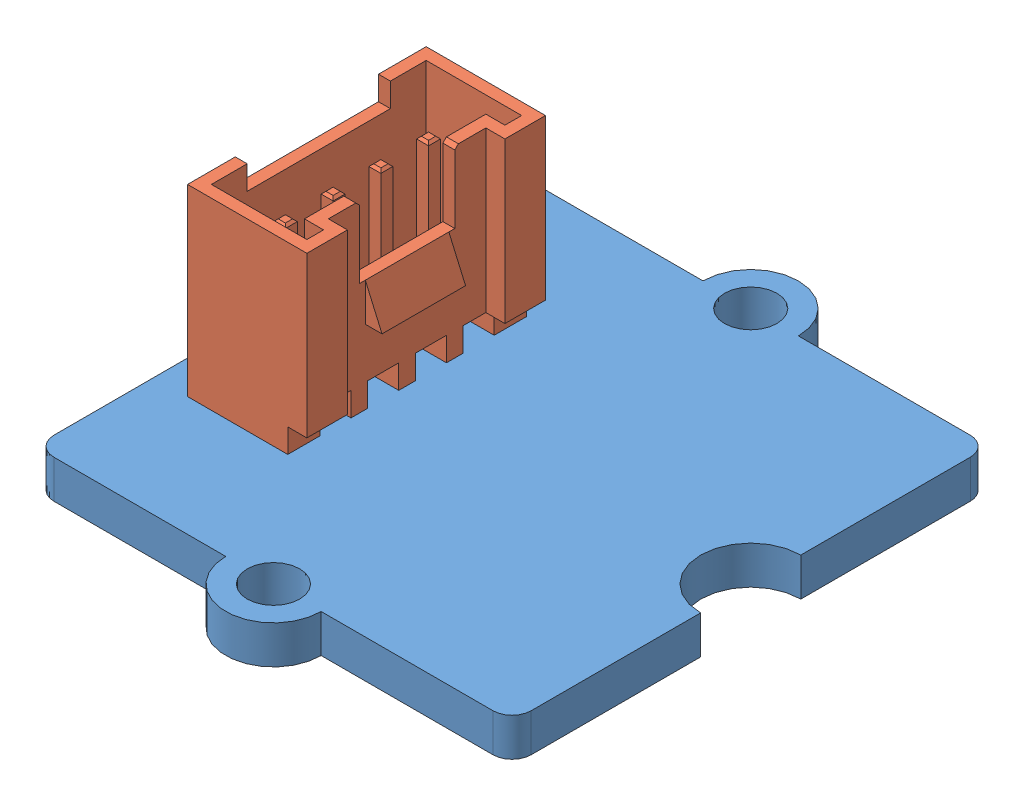
SolidWorks assembly PCB Grove 20x20 DIP - Buzzer, configuration Défaut. Lengths in mm.
Overall size (20 10 24).
2 component instances, 2 part files, 3 mates.
Components (placement in the parent):
- PCB Grove 20x20 - Buzzer v1.2-1: PCB Grove 20x20 - Buzzer v1.2 [Défaut] at (10.8609 7.7083 21.3176) size (20 1.6 24)
- Connector Grove DIP-1: Connector Grove DIP [Défaut] at (7.2609 8.5083 21.3176) x (0 0 -1) z (1 0 0) size (10 10 5)
Mates (geometry in assembly coordinates):
- Coïncidente1: coincident anti-aligned: plane of PCB Grove 20x20 - Grove Buzzer v1.2-1 through (10.8609 7.7083 21.3176) normal (0 0 1); plane of Connector Grove DIP-1 through (7.2609 8.5083 21.3176) normal (0 0 -1)
- Coïncidente2: coincident anti-aligned: plane of PCB Grove 20x20 - Grove Buzzer v1.2-1 through (10.8609 8.5083 21.3176) normal (0 1 0); plane of Connector Grove DIP-1 through (7.2609 8.5083 21.3176) normal (0 -1 0)
- Distance1: distance = 1.4 mm aligned: plane of Connector Grove DIP-1 through (2.2609 16.2083 26.3176) normal (-1 0 0); plane of PCB Grove 20x20 - Grove Buzzer v1.2-1 through (0.8609 8.5083 21.3176) normal (-1 0 0)
